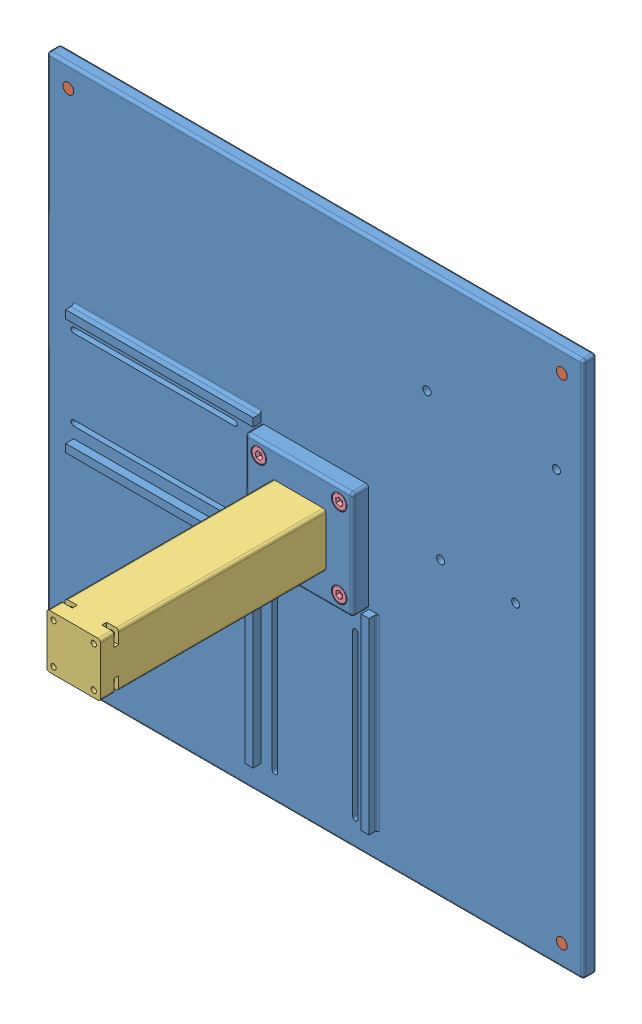
SolidWorks assembly socle-complet, configuration Défaut. Lengths in mm.
Overall size (200 200 99).
14 component instances, 5 part files, 31 mates.
Components (placement in the parent):
- socle-1: socle [Défaut] at (-29.167 0.8294 152.5) size (200 200 11)
- socle-patin-1: socle-patin [Défaut] at (-121.167 -91.1706 157.5) x (0 0 1) z (-1 0 0) size (8.5 12.12 12.12)
- socle-patin-2: socle-patin [Défaut] at (-121.167 92.8294 157.5) x (0 0 1) z (-0.96387 -0.266373 0) size (8.5 12.12 12.12)
- socle-patin-3: socle-patin [Défaut] at (62.833 92.8294 157.5) x (0 0 1) z (-0.99904 0.043817 0) size (8.5 12.12 12.12)
- socle-patin-4: socle-patin [Défaut] at (62.833 -91.1706 157.5) x (0 0 1) z (-1 0 0) size (8.5 12.12 12.12)
- socle_pied-1: socle_pied [Défaut] at (-29.167 0.8294 148.5) size (40 40 99)
- vis-chc-5: vis-chc [Vis CHC M3x12] at (-14.167 15.8294 160.5) x (-0.779324 -0.626621 0) z (-0.626621 0.779324 0) size (5.5 15 5.5)
- vis-chc-6: vis-chc [Vis CHC M3x12] at (-44.167 -14.1706 160.5) x (-0.389871 -0.920869 0) z (-0.920869 0.389871 0) size (5.5 15 5.5)
- vis-chc-7: vis-chc [Vis CHC M3x12] at (-44.167 15.8294 160.5) x (-0.37168 0.928361 0) z (0.928361 0.37168 0) size (5.5 15 5.5)
- vis-chc-8: vis-chc [Vis CHC M3x12] at (-14.167 -14.1706 160.5) x (0.851306 -0.524669 0) z (-0.524669 -0.851306 0) size (5.5 15 5.5)
- ecrou-h-5: ecrou-h [6012 HU M3] at (-44.167 15.8294 148.6) x (1 0 0) z (0 1 0) size (5.5 2.4 6.35)
- ecrou-h-6: ecrou-h [6012 HU M3] at (-44.167 -14.1706 148.6) x (1 0 0) z (0 1 0) size (5.5 2.4 6.35)
- ecrou-h-7: ecrou-h [6012 HU M3] at (-14.167 15.8294 148.6) x (1 0 0) z (0 1 0) size (5.5 2.4 6.35)
- ecrou-h-8: ecrou-h [6012 HU M3] at (-14.167 -14.1706 148.6) x (0.5 0.866025 0) z (-0.866025 0.5 0) size (5.5 2.4 6.35)
Mates (geometry in assembly coordinates):
- Coaxiale1: concentric anti-aligned: cylinder of socle-1 through (62.833 -91.1706 157.501) axis (0 0 -1) radius 2; cylinder of socle-patin-4 through (62.833 -91.1706 157.5) axis (0 0 1) radius 2
- Coïncidente1: coincident anti-aligned: plane of socle-1 through (-29.167 0.8294 152.5) normal (0 0 -1); plane of socle-patin-4 through (62.833 -93.1706 152.5) normal (0 0 1)
- Coaxiale2: concentric anti-aligned: cylinder of socle-1 through (-121.167 -91.1706 157.501) axis (0 0 -1) radius 2; cylinder of socle-patin-1 through (-121.167 -91.1706 157.5) axis (0 0 1) radius 2
- Coïncidente2: coincident anti-aligned: plane of socle-1 through (-29.167 0.8294 152.5) normal (0 0 -1); plane of socle-patin-1 through (-121.167 -93.1706 152.5) normal (0 0 1)
- Coaxiale3: concentric anti-aligned: cylinder of socle-1 through (-121.167 92.8294 157.501) axis (0 0 -1) radius 2; cylinder of socle-patin-2 through (-121.167 92.8294 157.5) axis (0 0 1) radius 2
- Coïncidente3: coincident anti-aligned: plane of socle-1 through (-29.167 0.8294 152.5) normal (0 0 -1); plane of socle-patin-2 through (-120.6343 90.9017 152.5) normal (0 0 1)
- Coaxiale4: concentric anti-aligned: cylinder of socle-1 through (62.833 92.8294 157.501) axis (0 0 -1) radius 2; cylinder of socle-patin-3 through (62.833 92.8294 157.5) axis (0 0 1) radius 2
- Coïncidente4: coincident anti-aligned: plane of socle-1 through (-29.167 0.8294 152.5) normal (0 0 -1); plane of socle-patin-3 through (62.7453 90.8313 152.5) normal (0 0 1)
- Coïncidente5: coincident anti-aligned: plane of socle-1 through (-29.167 0.8294 152.5) normal (0 0 -1); plane of socle_pied-1 through (-29.167 0.8294 152.5) normal (0 0 1)
- Coïncidente6: coincident anti-aligned: plane of socle-1 through (-39.167 10.8294 152.5) normal (0 -1 0); plane of socle_pied-1 through (-39.167 10.8294 247.5) normal (0 1 0)
- Coïncidente7: coincident anti-aligned: plane of socle-1 through (-19.167 10.8294 152.5) normal (-1 0 0); plane of socle_pied-1 through (-19.167 10.8294 247.5) normal (1 0 0)
- Coaxiale5: concentric aligned: cylinder of socle-1 through (-14.167 -14.1706 152.5) axis (0 0 1) radius 1.5; cylinder of vis-chc-8 through (-14.167 -14.1706 148.5) axis (0 0 1) radius 1.5
- Coaxiale6: concentric aligned: cylinder of socle-1 through (-14.167 15.8294 152.5) axis (0 0 1) radius 1.5; cylinder of vis-chc-5 through (-14.167 15.8294 148.5) axis (0 0 1) radius 1.5
- Coaxiale7: concentric aligned: cylinder of socle-1 through (-44.167 -14.1706 152.5) axis (0 0 1) radius 1.5; cylinder of vis-chc-6 through (-44.167 -14.1706 148.5) axis (0 0 1) radius 1.5
- Coaxiale8: concentric aligned: cylinder of socle-1 through (-44.167 15.8294 152.5) axis (0 0 1) radius 1.5; cylinder of vis-chc-7 through (-44.167 15.8294 148.5) axis (0 0 1) radius 1.5
- Coïncidente8: coincident anti-aligned: plane of socle-1 through (-44.167 15.8294 160.5) normal (0 0 1); plane of vis-chc-7 through (-44.167 15.8294 160.5) normal (0 0 -1)
- Coïncidente9: coincident anti-aligned: plane of socle-1 through (-44.167 -14.1706 160.5) normal (0 0 1); plane of vis-chc-6 through (-44.167 -14.1706 160.5) normal (0 0 -1)
- Coïncidente10: coincident anti-aligned: plane of socle-1 through (-14.167 -14.1706 160.5) normal (0 0 1); plane of vis-chc-8 through (-14.167 -14.1706 160.5) normal (0 0 -1)
- Coïncidente11: coincident anti-aligned: plane of socle-1 through (-14.167 15.8294 160.5) normal (0 0 1); plane of vis-chc-5 through (-14.167 15.8294 160.5) normal (0 0 -1)
- Coaxiale9: concentric anti-aligned: cylinder of vis-chc-7 through (-44.167 15.8294 148.5) axis (0 0 1) radius 1.5; cylinder of ecrou-h-5 through (-44.167 15.8294 151) axis (0 0 -1) radius 1.2295
- Coïncidente12: coincident anti-aligned: plane of socle_pied-1 through (-29.167 0.8294 151) normal (0 0 -1); plane of ecrou-h-5 through (-41.417 14.2417 151) normal (0 0 1)
- Parallèle1: parallel anti-aligned: plane of socle_pied-1 through (-44.167 12.6294 151) normal (0.5 0.866025 0); plane of ecrou-h-5 through (-44.167 12.654 151) normal (-0.5 -0.866025 0)
- Coaxiale10: concentric anti-aligned: cylinder of vis-chc-6 through (-44.167 -14.1706 148.5) axis (0 0 1) radius 1.5; cylinder of ecrou-h-6 through (-44.167 -14.1706 151) axis (0 0 -1) radius 1.2295
- Parallèle2: parallel anti-aligned: plane of socle_pied-1 through (-44.167 -17.3706 151) normal (0.5 0.866025 0); plane of ecrou-h-6 through (-44.167 -17.346 151) normal (-0.5 -0.866025 0)
- Coïncidente15: coincident anti-aligned: plane of socle_pied-1 through (-29.167 0.8294 151) normal (0 0 -1); plane of ecrou-h-6 through (-41.417 -15.7583 151) normal (0 0 1)
- Coaxiale11: concentric anti-aligned: cylinder of vis-chc-8 through (-14.167 -14.1706 148.5) axis (0 0 1) radius 1.5; cylinder of ecrou-h-8 through (-14.167 -14.1706 151) axis (0 0 -1) radius 1.2295
- Parallèle3: parallel aligned: plane of socle_pied-1 through (-16.9383 -12.5706 151) normal (0.5 -0.866025 0); plane of ecrou-h-8 through (-11.417 -15.7583 151) normal (0.5 -0.866025 0)
- Coïncidente17: coincident anti-aligned: plane of socle_pied-1 through (-29.167 0.8294 151) normal (0 0 -1); plane of ecrou-h-8 through (-11.417 -12.5829 151) normal (0 0 1)
- Coaxiale12: concentric anti-aligned: cylinder of vis-chc-5 through (-14.167 15.8294 148.5) axis (0 0 1) radius 1.5; cylinder of ecrou-h-7 through (-14.167 15.8294 151) axis (0 0 -1) radius 1.2295
- Parallèle4: parallel anti-aligned: plane of socle_pied-1 through (-14.167 12.6294 151) normal (0.5 0.866025 0); plane of ecrou-h-7 through (-14.167 12.654 151) normal (-0.5 -0.866025 0)
- Coïncidente19: coincident anti-aligned: plane of socle_pied-1 through (-29.167 0.8294 151) normal (0 0 -1); plane of ecrou-h-7 through (-11.417 14.2417 151) normal (0 0 1)
